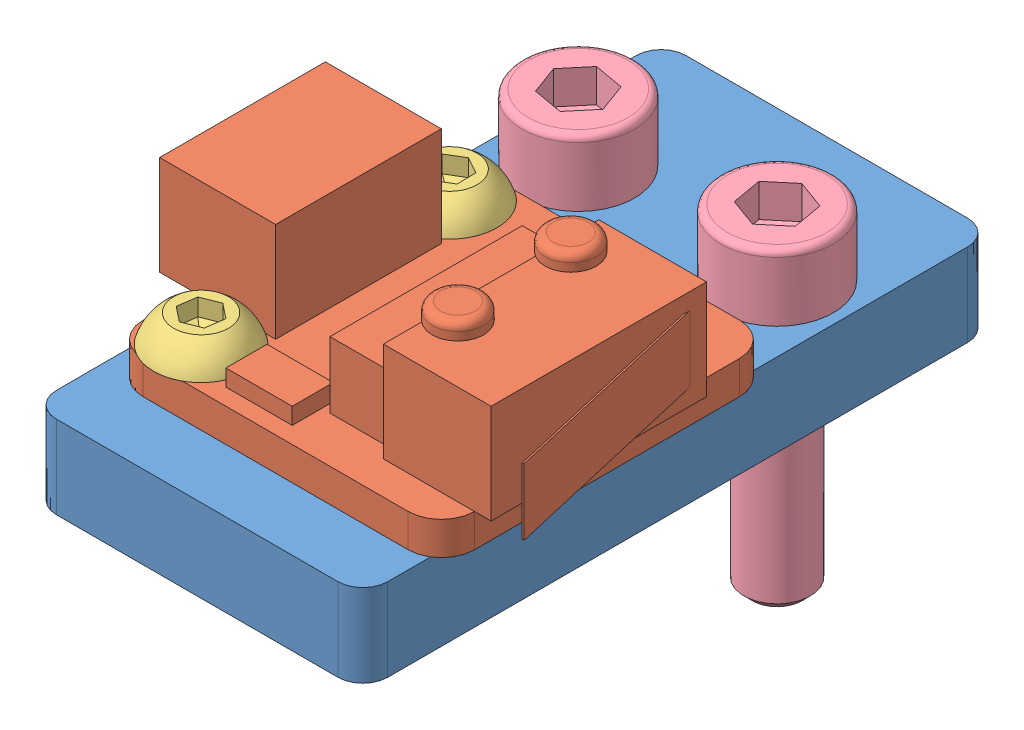
SolidWorks assembly ASM Y-Axis Limit Switch, configuration Standard. Lengths in mm.
Overall size (26 25 38).
6 component instances, 4 part files, 14 mates.
Components (placement in the parent):
- Y limit switch bracket-1: Y limit switch bracket [Standard] at origin size (20 5 38)
- limit switch-1: limit switch [Standard] at (-235.05 67.4999 7.213) x (-1 0 0) z (0 1 0) size (26 20 11)
- M3X6Pan Head Screw-1: M3X6Pan Head Screw [Standard] at (-242.05 71.1499 14.713) x (0 -1 0) z (-0.928687 0 0.370866) size (8.15 6.02 6.02)
- M4X16 Screw-1: M4X16 Screw [Standard] at (-242 67.4999 -8) x (0 -1 0) z (-0.173648 0 0.984808) size (20 6.8 6.8)
- M4X16 Screw-2: M4X16 Screw [Standard] at (-230 67.4999 -8) x (0 -1 0) z (-0.34202 0 0.939693) size (20 6.8 6.8)
- M3X6Pan Head Screw-2: M3X6Pan Head Screw [Standard] at (-242.05 71.1499 -0.287) x (0 -1 0) z (-0.858137 0 0.51342) size (8.15 6.02 6.02)
Mates (geometry in assembly coordinates):
- Konzentrisch15: concentric aligned: cylinder of Y limit switch bracket-1 through (-249.4143 67.4999 -8) axis (0 1 0) radius 2.35; cylinder of M4X16 Screw-1 through (-249.4143 68.4415 -8) axis (0 1 0) radius 2
- Deckungsgleich21: coincident anti-aligned: plane of Y limit switch bracket-1 through (-243.4143 67.4999 3.5) normal (0 1 0); plane of M4X16 Screw-1 through (-246.066 67.4999 -7.4096) normal (0 -1 0)
- Konzentrisch16: concentric aligned: cylinder of Y limit switch bracket-1 through (-237.4143 67.4999 -8) axis (0 1 0) radius 2.35; cylinder of M4X16 Screw-2 through (-237.4143 68.4415 -8) axis (0 1 0) radius 2
- Deckungsgleich22: coincident anti-aligned: plane of Y limit switch bracket-1 through (-243.4143 67.4999 3.5) normal (0 1 0); plane of M4X16 Screw-2 through (-234.2194 67.4999 -6.8371) normal (0 -1 0)
- Konzentrisch17: concentric aligned: cylinder of Y limit switch bracket-1 through (-249.4643 61.9999 14.713) axis (0 1 0) radius 1.3; cylinder of limit switch-1 through (-249.4643 67.2999 14.713) axis (0 1 0) radius 1.55
- Konzentrisch18: concentric aligned: cylinder of Y limit switch bracket-1 through (-249.4643 61.9999 -0.287) axis (0 1 0) radius 1.3; cylinder of limit switch-1 through (-249.4643 67.2999 -0.287) axis (0 1 0) radius 1.55
- Deckungsgleich23: coincident anti-aligned: plane of Y limit switch bracket-1 through (-243.4143 67.4999 3.5) normal (0 1 0); plane of limit switch-1 through (-242.4643 67.4999 7.213) normal (0 -1 0)
- Konzentrisch19: concentric aligned: cylinder of limit switch-1 through (-249.4643 67.2999 14.713) axis (0 1 0) radius 1.55; cylinder of M3X6Pan Head Screw-1 through (-249.4643 63.4999 14.713) axis (0 1 0) radius 1.5
- Deckungsgleich24: coincident anti-aligned: plane of limit switch-1 through (-242.4643 69.4999 7.213) normal (0 1 0); plane of M3X6Pan Head Screw-1 through (-249.4643 69.4999 14.713) normal (0 -1 0)
- Konzentrisch20: concentric aligned: cylinder of limit switch-1 through (-249.4643 67.2999 -0.287) axis (0 1 0) radius 1.55; cylinder of M3X6Pan Head Screw-2 through (-249.4643 63.4999 -0.287) axis (0 1 0) radius 1.5
- Deckungsgleich25: coincident anti-aligned: plane of limit switch-1 through (-242.4643 69.4999 7.213) normal (0 1 0); plane of M3X6Pan Head Screw-2 through (-249.4643 69.4999 -0.287) normal (0 -1 0)
- Deckungsgleich26: coincident aligned: plane of ? through (-7.4143 0 0) normal (0 0 1)
- Deckungsgleich27: coincident aligned: plane of ? through (-7.4143 0 0) normal (0 1 0)
- Deckungsgleich28: coincident aligned: plane of Y limit switch bracket-1 through (0 0 0) normal (1 0 0); plane of assembly
